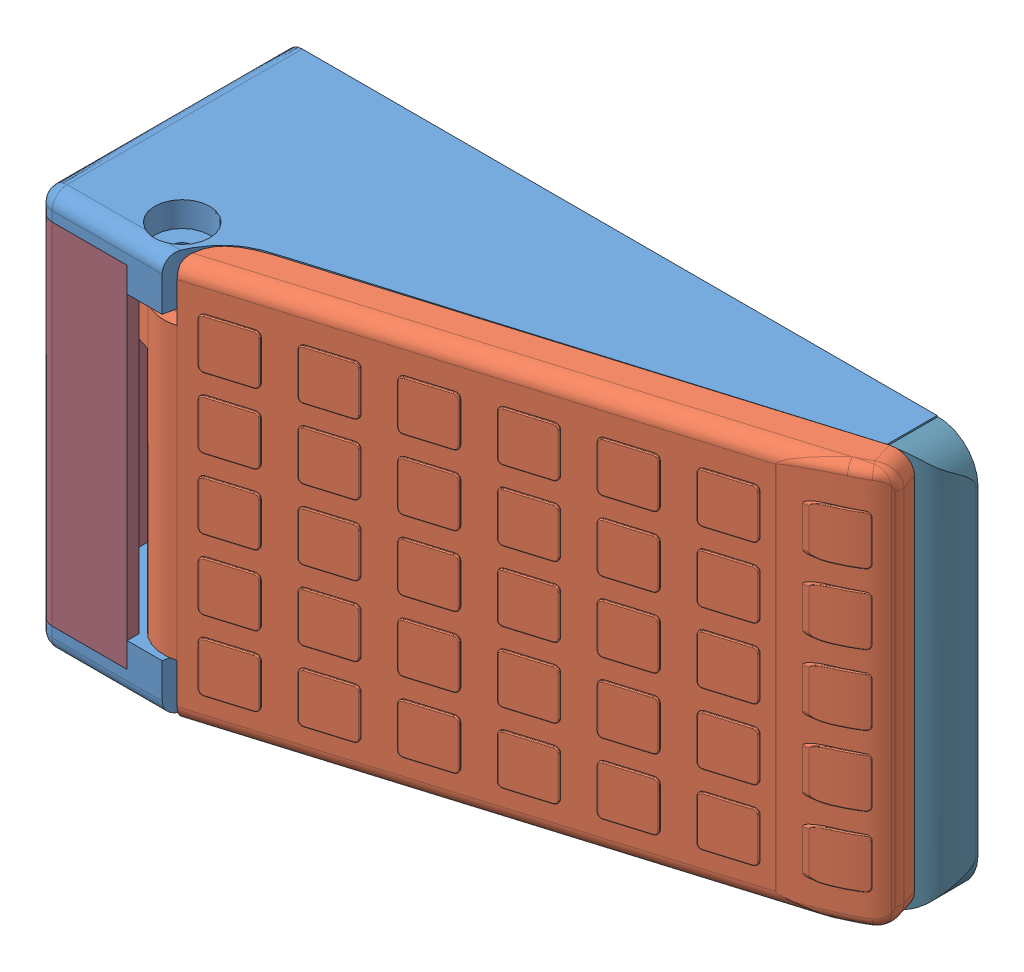
SolidWorks assembly pedal assm, configuration Default. Lengths in mm.
Overall size (138.12 80.54 54).
15 component instances, 14 part files, 20 mates.
Components (placement in the parent):
- base-1: base [Default] at origin size (130 80 50)
- pedal-1: pedal [Default] at (16.9881 0 32.9198) x (-0.95701 0 0.290054) z (-0.290054 0 -0.95701) size (123.52 80.54 18.09)
- switch assm-1: switch assm [Default] at (-25.6281 -30 22.893) x (0.944943 0 -0.327235) z (0 1 0) size (64.7 27.58 9.95)
  - switchbody-1: switchbody [Default] at origin size (39.45 19.3 9.95)
  - button-1: button [Default] at (8.275 -4.8104 4.975) x (1 0 0) z (0 -1 0) size (2.6 4 5.6)
  - lever-1: lever [Default] at (15.4957 -10.5167 3.3323) x (-0.999858 0.016849 0) z (0 0 1) size (41.75 10.59 4)
- peg spring-1: peg spring [Default] at (-44 9.5 42) x (0.998467 0 -0.05535) z (0 1 0) size (18.54 12.06 13)
- spring cap-1: spring cap [Default] at (-37.4347 20.9117 32.027) x (-1 0 0) z (0 0 -1) size (19 21 10)
- pot slide-1: pot slide [Default] at (4.132 4 28.4569) x (0.962615 0 -0.270872) z (0 -1 0) size (17.25 26.03 8)
- pot-1: pot [Default] at (-2.5 28.8 17) x (-0.35893 0 -0.933365) z (0 -1 0) size (26.3 28.7 34.8)
- pot cog-1: pot cog [Default] at (-2.5 4 17) x (0.053192 0 0.998584) z (0 -1 0) size (11.16 10.99 10)
- pot clamp-1: pot clamp [Default] at (-2.5 17 21) x (1 0 0) z (0 -1 0) size (20 6 4)
- teensy3.1-1: teensy3.1 [Default] at (-44.0338 -12.5843 4.1633) size (36.43 18 4.29)
- back panel-1: back panel [Default] at (-56 35 27) x (0 0 1) z (0 -1 0) size (46 18 70)
- front panel-1: front panel [Default] at (69.1152 -0.1853 -0.0642) size (8.81 80 11.22)
Mates (geometry in assembly coordinates):
- Distance2: distance = 1 mm anti-aligned: plane of pedal-1 through (-41.6222 -29 36.0547) normal (0 -1 0); plane of base-1 through (-65 -30 -143.1782) normal (0 1 0)
- Concentric5: concentric aligned: cylinder of pedal-1; circle of peg spring-1
- Distance4: distance = 0.5 mm anti-aligned: plane of pedal-1 through (-33.4581 9 44.0295) normal (0 1 0); plane of peg spring-1 through (-44 9.5 42) normal (0 -1 0)
- Coincident7: coincident anti-aligned: plane of base-1 through (-65 -30 -143.1782) normal (0 1 0); plane of switch assm-1/switchbody-1 through (-36.2486 -30 34.9311) normal (0 -1 0)
- Concentric7: concentric anti-aligned: circle of base-1; circle of switch assm-1/switchbody-1
- Parallel3: parallel aligned: plane of pedal-1 through (69.2173 -40 8.7306) normal (0 -1 0); plane of pot slide-1 through (-43.9988 -4 42.0005) normal (0 -1 0)
- Concentric9: concentric aligned: circle of base-1; circle of pot-1
- Coincident10: coincident anti-aligned: plane of base-1 through (-12.5 17 18) normal (0 1 0); plane of pot-1 through (-2.5 17 17) normal (0 -1 0)
- Concentric10: concentric anti-aligned: circle of pedal-1; circle of pot slide-1
- Coincident11: coincident anti-aligned: plane of pedal-1 through (-5.1969 5.05 32.3293) normal (-0.290054 0 -0.95701); plane of pot slide-1 through (-5.15 -4 32.3151) normal (0.290054 0 0.95701)
- Concentric11: concentric aligned: cylinder of pot-1; cylinder of pot cog-1
- Coincident12: coincident aligned: plane of pot-1 through (-2.5 -6 17) normal (0 -1 0); plane of pot cog-1 through (-2.5 -6 17) normal (0 -1 0)
- Coincident13: coincident aligned: circle of base-1; circle of pot clamp-1
- Coincident14: coincident aligned: plane of base-1 through (-12.5 13 18) normal (0 -1 0); plane of pot clamp-1 through (-2.5 13 17) normal (0 -1 0)
- Concentric12: concentric anti-aligned: circle of spring cap-1; circle of base-1
- Parallel4: parallel anti-aligned: plane of spring cap-1 through (-30.4347 29.9117 27.027) normal (0 1 0); plane of base-1 through (-65 30 -143.1782) normal (0 -1 0)
- Concentric13: concentric aligned: cylinder of base-1; circle of pedal-1
- Coincident16: coincident anti-aligned: plane of back panel-1 through (-47 -35 47.6) normal (0 0 -1); plane of base-1 through (-62 30 47.6) normal (0 0 1)
- Coincident17: coincident anti-aligned: plane of base-1 through (-62 30 -1.831) normal (-1 0 0); plane of back panel-1 through (-62 -35 4) normal (1 0 0)
- Coincident19: coincident anti-aligned: plane of base-1 through (-65 -35 -1.831) normal (0 1 0); plane of back panel-1 through (-62 -35 4) normal (0 -1 0)
